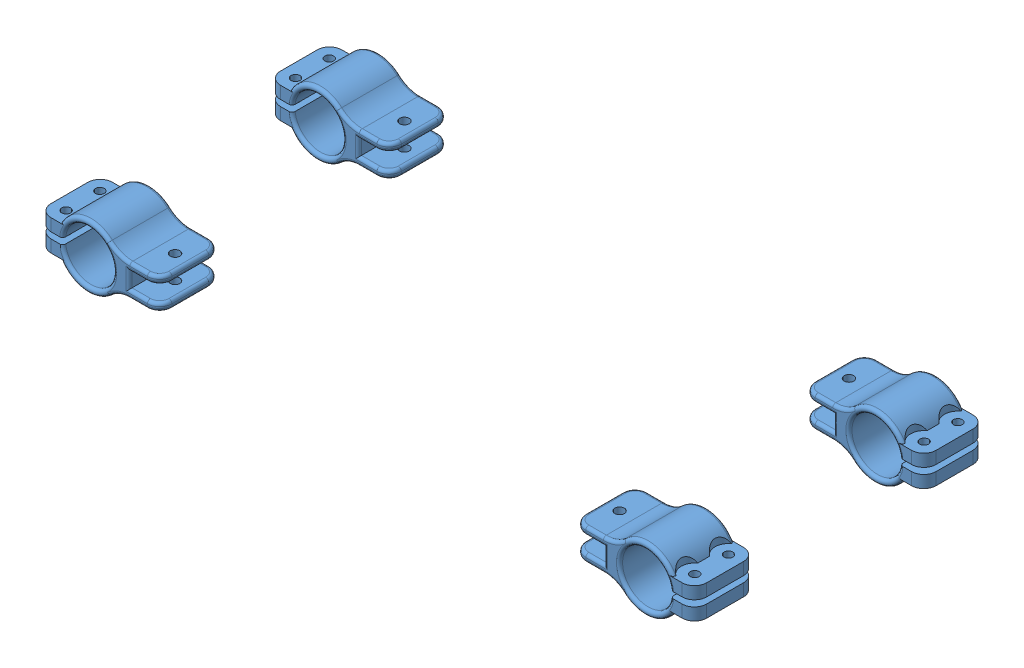
SolidWorks assembly fan_frame, configuration Default. Lengths in mm.
Overall size (271.29 26.52 120.57).
4 component instances, 1 part files, 12 mates.
Components (placement in the parent):
- clamp_for_x-1: clamp_for_x [默认] at (-48.0342 75.7222 224.2378) size (50.04 26.27 25.65)
- clamp_for_x-2: clamp_for_x [默认] at (41.0609 75.4682 249.6378) x (-1 0 0) z (0 0 -1) size (50.04 26.27 25.65)
- clamp_for_x-3: clamp_for_x [默认] at (41.0609 75.4682 154.7178) x (-1 0 0) z (0 0 -1) size (50.04 26.27 25.65)
- clamp_for_x-4: clamp_for_x [默认] at (-48.0342 75.7222 129.3178) size (50.04 26.27 25.65)
Mates (geometry in assembly coordinates):
- 同心1: concentric: cylinder of xframe_z-1 through (-95.4531 78.7702 236.9378) axis (0 -1 0) radius 1.984; cylinder of clamp_for_x-1 through (-95.4531 79.0242 236.9378) axis (0 -1 0) radius 1.9844
- 重合1: coincident: plane of xframe_z-1 through (-3.1933 72.4202 174.711) normal (0 -1 0); plane of clamp_for_x-1 through (-94.1831 72.4202 249.6378) normal (0 1 0)
- 同心2: concentric: cylinder of xframe_z-1 through (-95.4531 78.7702 142.0178) axis (0 -1 0) radius 1.984; cylinder of clamp_for_x-4 through (-95.4531 72.4202 142.0178) axis (0 1 0) radius 1.9844
- 重合2: coincident: plane of xframe_z-1 through (-3.1933 72.4202 174.711) normal (0 -1 0); plane of clamp_for_x-4 through (-94.1831 72.4202 154.7178) normal (0 1 0)
- 重合3: coincident anti-aligned: plane of xframe_z-1 through (-101.8031 78.7702 129.3178) normal (-1 0 0); plane of clamp_for_x-4 through (-101.8031 75.7222 129.3178) normal (1 0 0)
- 重合4: coincident anti-aligned: plane of xframe_z-1 through (-101.8031 78.7702 129.3178) normal (-1 0 0); plane of clamp_for_x-1 through (-101.8031 75.7222 224.2378) normal (1 0 0)
- 同心3: concentric: cylinder of xframe_z-1 through (88.4797 78.7702 236.9378) axis (0 -1 0) radius 1.984; cylinder of clamp_for_x-2 through (88.4797 72.1662 236.9378) axis (0 1 0) radius 1.9844
- 重合5: coincident: plane of xframe_z-1 through (94.8297 78.7702 129.3178) normal (1 0 0); plane of clamp_for_x-2 through (94.8297 75.4682 249.6378) normal (-1 0 0)
- 重合6: coincident anti-aligned: plane of xframe_z-1 through (-3.1933 78.7702 174.711) normal (0 1 0); plane of clamp_for_x-2 through (87.2097 78.7702 249.6378) normal (0 -1 0)
- 同心4: concentric: cylinder of xframe_z-1 through (88.4797 78.7702 142.0178) axis (0 -1 0) radius 1.984; cylinder of clamp_for_x-3 through (88.4797 72.1662 142.0178) axis (0 1 0) radius 1.9844
- 重合7: coincident: plane of xframe_z-1 through (94.8297 78.7702 129.3178) normal (1 0 0); plane of clamp_for_x-3 through (94.8297 75.4682 154.7178) normal (-1 0 0)
- 重合8: coincident anti-aligned: plane of xframe_z-1 through (-3.1933 78.7702 174.711) normal (0 1 0); plane of clamp_for_x-3 through (87.2097 78.7702 154.7178) normal (0 -1 0)
